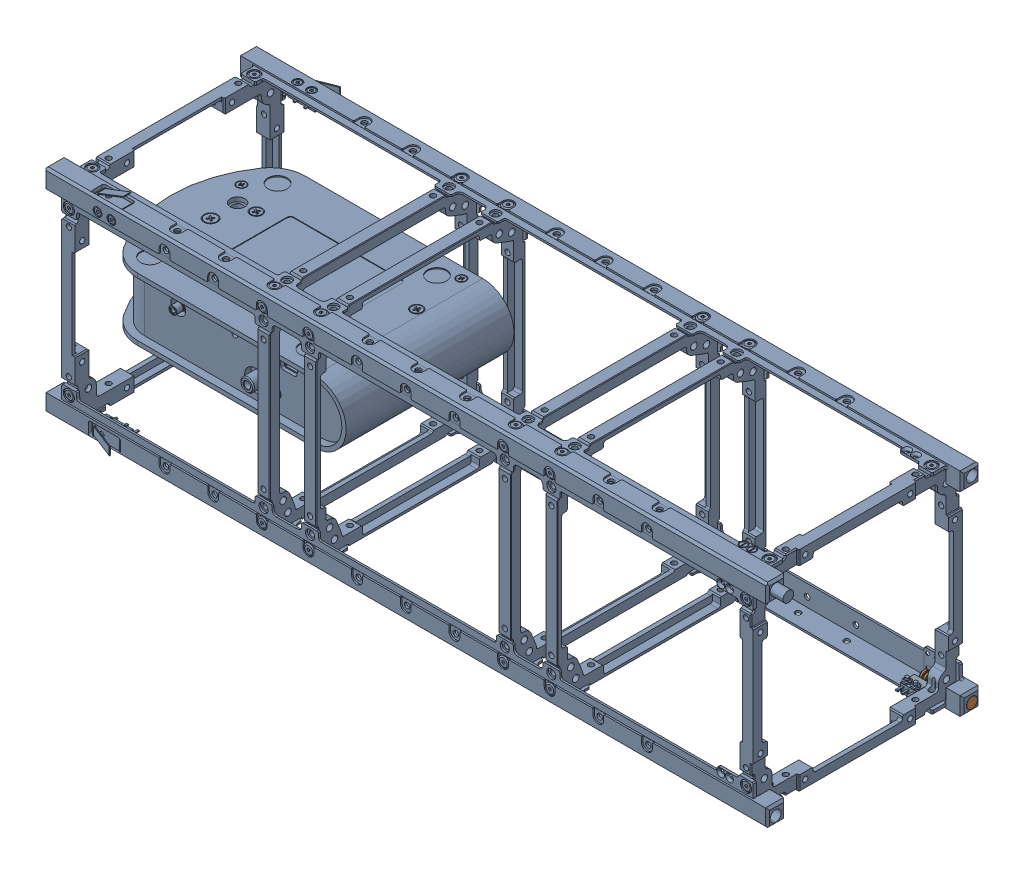
SolidWorks assembly 3U Satellite Assembly 2, configuration Default. Lengths in mm.
Overall size (346.5 108.91 108.91).
2 component instances, 2 part files, 0 mates.
Components (placement in the parent):
- satsearch_cad-model_gnyz4g_npc_spacemind_sm03-cubesat-structure-1: satsearch_cad-model_gnyz4g_npc_spacemind_sm03-cubesat-structure [Default] at (48.8956 -7.5636 162.2083) size (346.5 108.91 108.91)
- CCS100_M-Solidworks-1: CCS100_M-Solidworks [Standard] at (-86.2771 47.5087 153.3271) size (122.02 29.5 79.5)
